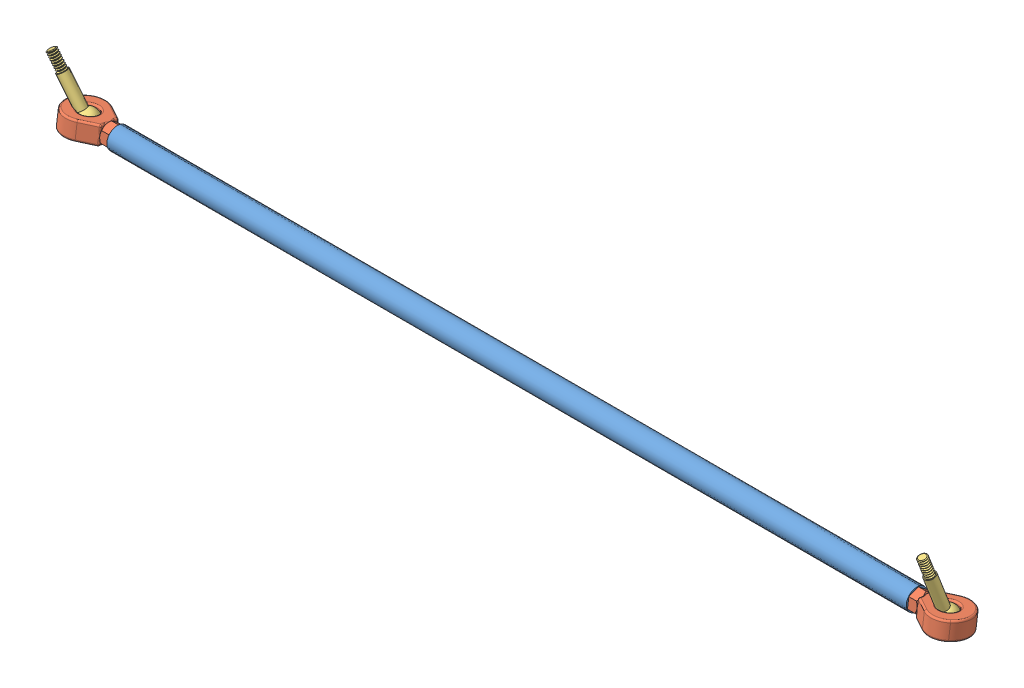
SolidWorks assembly Tie rod new, configuration Default. Lengths in mm.
Overall size (129.97 10.68 7.29).
5 component instances, 3 part files, 7 mates.
Components (placement in the parent):
- shaft 1-1: shaft 1 [Default] at (89.9917 135.8608 189.9837) size (112.5 3 3)
- Tie Rod screw-1: Tie Rod screw [Default] at (77.4922 135.8608 189.9837) x (1 0 0) z (0 0.134863 0.990864) size (14.74 3.17 5.65)
- Tie Rod screw-2: Tie Rod screw [Default] at (214.9912 135.8608 189.9837) x (-1 0 0) z (0 -0.134863 -0.990864) size (14.74 3.17 5.65)
- Part1 (M5 shoulder screw)-1: Part1 (M5 shoulder screw) [Default] at (74.6027 154.7341 192.3663) x (0.666578 0.308172 0.678751) z (0.547649 0.415281 -0.726377) size (3 9.75 3)
- Part1 (M5 shoulder screw)-3: Part1 (M5 shoulder screw) [Default] at (203.5893 156.7899 196.1763) x (-0.449676 -0.314787 0.835883) z (0.881769 -0.00726 0.471626) size (3 9.75 3)
Mates (geometry in assembly coordinates):
- Concentric1: concentric aligned: cylinder of shaft 1-1 through (172.4917 135.8608 189.9837) axis (1 0 0) radius 0.75; cylinder of Tie Rod screw-1 through (194.9917 135.8608 189.9837) axis (1 0 0) radius 0.75
- Concentric3: concentric aligned: cylinder of shaft 1-1 through (119.9917 135.8608 189.9837) axis (-1 0 0) radius 0.75; cylinder of Tie Rod screw-2 through (97.4917 135.8608 189.9837) axis (-1 0 0) radius 0.75
- Concentric4: concentric: sphere of Tie Rod screw-2; sphere of Part1 (M5 shoulder screw)-1
- Concentric5: concentric: sphere of Tie Rod screw-1; sphere of Part1 (M5 shoulder screw)-3
- Coincident3: coincident aligned: plane of Tie Rod screw-1 through (207.109 134.6661 190.4745) normal (0 -0.990864 0.134863); plane of Tie Rod screw-2 through (85.3744 134.5783 189.8301) normal (0 -0.990864 0.134863)
- Coincident4: coincident anti-aligned: plane of shaft 1-1 through (202.4917 135.8608 189.9837) normal (1 0 0); plane of Tie Rod screw-1 through (202.4917 135.8608 189.9837) normal (-1 0 0)
- Coincident5: coincident anti-aligned: plane of shaft 1-1 through (89.9917 135.8608 189.9837) normal (-1 0 0); plane of Tie Rod screw-2 through (89.9917 135.8608 189.9837) normal (1 0 0)
